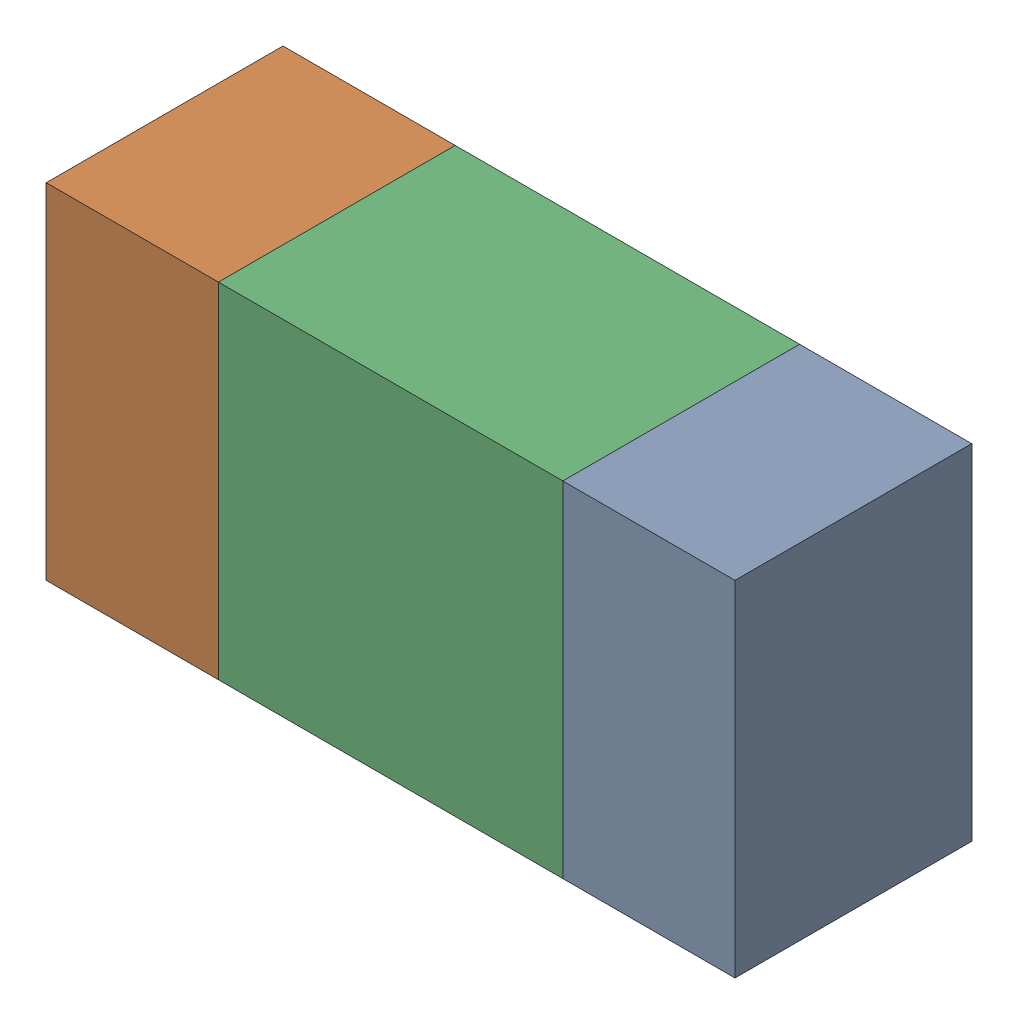
SolidWorks assembly R1, configuration ﾃﾞﾌｫﾙﾄ. Lengths in mm.
Overall size (1.6 0.8 0.55).
6 component instances, 2 part files, 0 mates.
Components (placement in the parent):
- 689261512-1: 689261512 [ﾃﾞﾌｫﾙﾄ] at (62.8999 43.7499 0) size (0.4 0.8 0.55)
  - Extruded_32-1: Extruded_32 [ﾃﾞﾌｫﾙﾄ] at origin size (0.4 0.8 0.55)
- 689261512-2: 689261512 [ﾃﾞﾌｫﾙﾄ] at (61.6999 43.7499 0) size (0.4 0.8 0.55)
  - Extruded_32-1: Extruded_32 [ﾃﾞﾌｫﾙﾄ] at origin size (0.4 0.8 0.55)
- 689261648-1: 689261648 [ﾃﾞﾌｫﾙﾄ] at (62.3 43.7499 0) size (0.8 0.8 0.55)
  - Extruded_33-1: Extruded_33 [ﾃﾞﾌｫﾙﾄ] at origin size (0.8 0.8 0.55)
